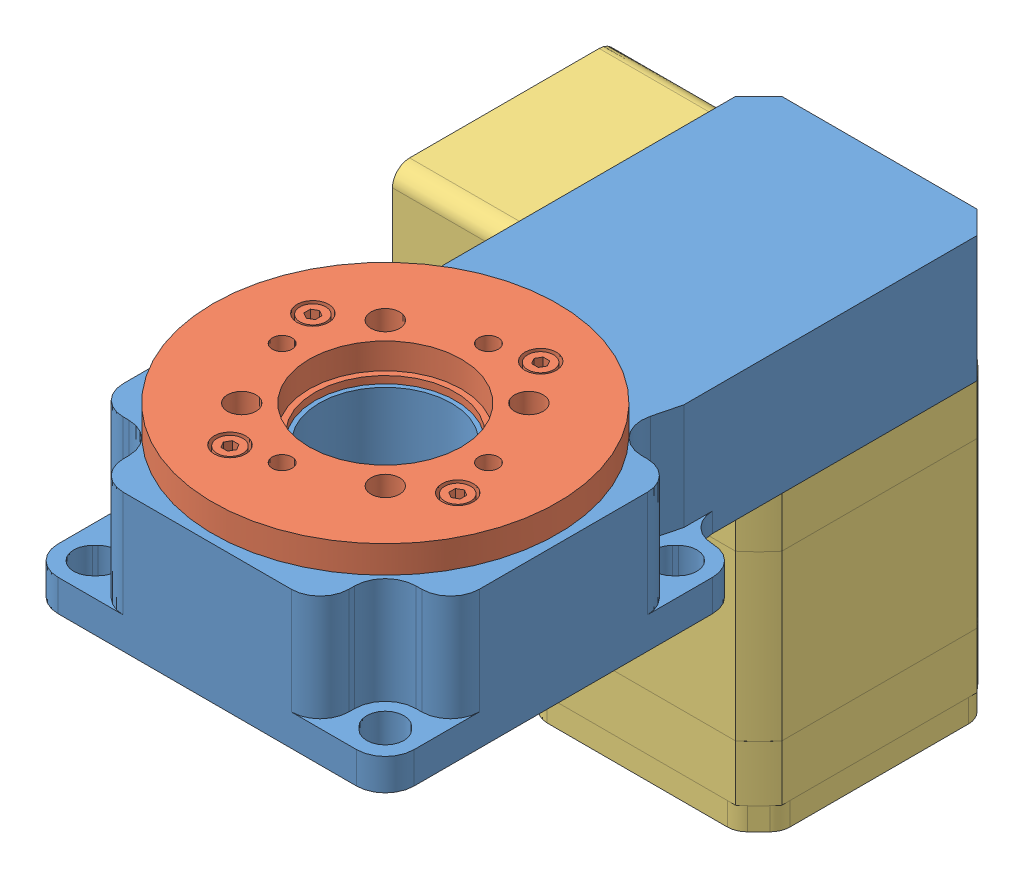
SolidWorks assembly RSB60, configuration RSB60xD-T3A. Lengths in mm.
Overall size (76 78.15 118.89).
3 component instances, 3 part files, 8 mates.
Components (placement in the parent):
- RSB60_base^RSB60-1: RSB60_base^RSB60 [Default] at origin (virtual)
- RSW60_top^RSB60-1: RSW60_top^RSB60 [RSW60] at (0 -2.5 0) (virtual)
- NMS17_motor^RSB60-1: NMS17_motor^RSB60 [RSB60-T3A] at (0 2.1 -65) x (-1 0 0) z (0 1 0) size (66 43.89 71) (virtual)
Mates (geometry in assembly coordinates):
- Distance1: distance = 2.5 mm aligned: plane of RSW60_top^RSB60-1 through (0 -2.5 0) normal (0 1 0); plane of assembly through (0 0 0) normal (0 1 0)
- Coincident2: coincident: point of RSW60_top^RSB60-1; plane of assembly
- Coincident3: coincident: point of RSW60_top^RSB60-1; plane of assembly
- Coincident5: coincident anti-aligned: plane of RSB60_base^RSB60-1 through (-26 24 -26) normal (0 1 0); plane of NMS17_motor^RSB60-1
- Coincident6: coincident: point of NMS17_motor^RSB60-1; plane of assembly
- Distance2: distance = 65 mm aligned: plane of NMS17_motor^RSB60-1; plane of assembly through (0 0 0) normal (0 0 1)
- Coincident7: coincident anti-aligned: plane of RSB60_base^RSB60-1 through (16.0332 2.1 -25.67) normal (0 -1 0); plane of NMS17_motor^RSB60-1 through (0 2.1 -65) normal (0 1 0)
- Home Position: coincident aligned: plane of RSW60_top^RSB60-1 through (0 -2.5 0) normal (0 0 1); plane of assembly through (0 0 0) normal (0 0 1)
